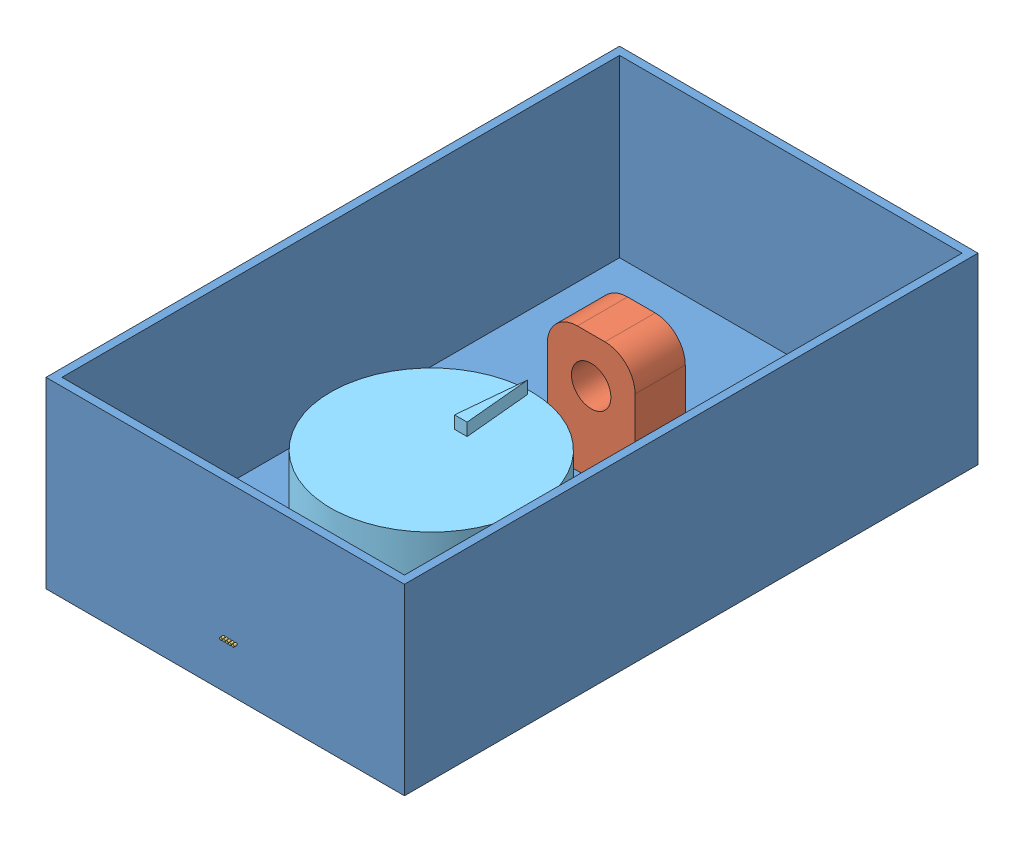
SolidWorks assembly Assembly, configuration Default. Lengths in mm.
Overall size (142.88 73.03 229.88).
6 component instances, 5 part files, 7 mates.
Components (placement in the parent):
- Basic-ForSizing-1: Basic-ForSizing [Default] at (174.0288 30.0127 122.1978) size (142.88 73.02 228.6)
- piston_holder-1: piston_holder [Default] at (189.9538 30.0127 118.8692) size (35 50 20)
- stepper_holder_flat-1: stepper_holder_flat [Default] at (211.9053 94.352 273.01) x (-1 0 0) z (0 -1 0) size (42 61 29.32)
  - Step Motor (28BYJ-48)-1: Step Motor (28BYJ-48) [Varsayılan] at (21.2606 45.5238 45.0393) size (42 61 29.02)
  - stepper_holder_28BYJ-48-flat-1: stepper_holder_28BYJ-48-flat [Default] at (20.4592 39.4575 43.5393) x (1 0 0) z (0 -1 0) size (42 20.8 25)
- cam-1: cam [Default] at (190.6447 51.3127 207.9862) size (80.16 25 80.16)
Mates (geometry in assembly coordinates):
- Coincident1: coincident anti-aligned: plane of Basic-ForSizing-1 through (174.0288 30.0127 122.1978) normal (0 1 0); plane of piston_holder-1 through (189.9538 30.0127 118.8692) normal (0 -1 0)
- Parallel1: parallel anti-aligned: plane of Basic-ForSizing-1 through (120.4802 99.8627 270.0345) normal (0 0 -1); plane of piston_holder-1 through (173.6185 80.0127 129.7244) normal (0 0 1)
- Coincident2: coincident anti-aligned: plane of Basic-ForSizing-1 through (174.0288 30.0127 122.1978) normal (0 1 0); plane of stepper_holder_flat-1/stepper_holder_28BYJ-48-flat-1 through (190.6447 30.0127 227.5656) normal (0 -1 0)
- Parallel2: parallel anti-aligned: plane of Basic-ForSizing-1 through (120.4802 99.8627 270.0345) normal (0 0 -1); plane of stepper_holder_flat-1/stepper_holder_28BYJ-48-flat-1 through (211.6447 49.3127 249.0256) normal (0 0 1)
- Coincident3: coincident anti-aligned: plane of stepper_holder_flat-1/Step Motor (28BYJ-48)-1 through (188.6447 59.3127 217.9862) normal (0 0 -1); plane of cam-1 through (188.1447 59.3127 217.9862) normal (0 0 1)
- Coincident4: coincident: moEndPointRef_w of stepper_holder_flat-1/Step Motor (28BYJ-48)-1; plane of cam-1 through (193.1447 59.3127 217.9862) normal (-1 0 0)
- Coincident5: coincident anti-aligned: plane of stepper_holder_flat-1/Step Motor (28BYJ-48)-1 through (190.6447 59.3127 219.4862) normal (0 1 0); plane of cam-1 through (190.6447 59.3127 207.9862) normal (0 -1 0)
